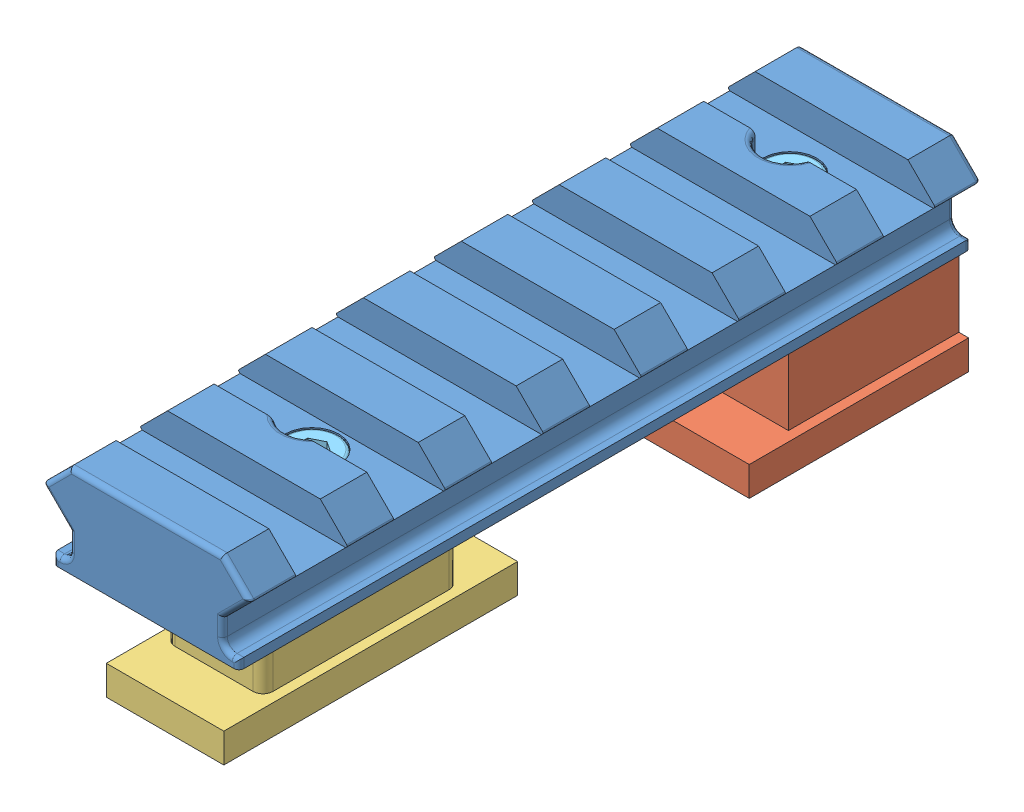
SolidWorks assembly Rail, configuration Standard. Lengths in mm.
Overall size (21.08 20.45 74.75).
7 component instances, 5 part files, 16 mates.
Components (placement in the parent):
- Rail-3: Rail [Standard] at (-4.1271 5.1584 0) size (21.08 9.45 74.75)
- flip_back-3: flip_back [Standard] at (-4.1271 -4.2416 0) x (0 0 1) z (-1 0 0) size (22.4 11 18.5)
- flip_front-1: flip_front [Standard] at (-4.1271 -4.2416 57.8) x (0 0 -1) z (1 0 0) size (30 11 12)
- hex nut style 1 gradeab_din-1: hex nut style 1 gradeab_din [Hexagon Nut ISO 4032 - M3 - D - S] at (-4.2271 -8.2416 9.0577) x (-1 0 0) z (0 1 0) size (5.5 6.35 2.4)
- hex nut style 1 gradeab_din-2: hex nut style 1 gradeab_din [Hexagon Nut ISO 4032 - M3 - D - S] at (-4.3271 -8.2416 57.8) x (1 0 0) z (0 1 0) size (5.5 6.35 2.4)
- socket head cap screw 4762_din-1: socket head cap screw 4762_din [ISO 4762 M3 x 10 --- 10S] at (-4.1271 2.1584 9) x (0 -1 0) z (-0.546944 0 0.837169) size (13 5.5 5.5)
- socket head cap screw 4762_din-2: socket head cap screw 4762_din [ISO 4762 M3 x 10 --- 10S] at (-4.1271 2.1584 57.8) x (0 -1 0) z (-0.546944 0 0.837169) size (13 5.5 5.5)
Mates (geometry in assembly coordinates):
- Deckungsgleich7: coincident: plane of Rail-3 through (5.3729 -4.2416 74.75) normal (0 -1 0); plane of flip_back-3 through (-13.3771 -4.2416 0) normal (0 1 0)
- Deckungsgleich11: coincident: plane of flip_front-1 through (1.8729 -4.2416 72.8) normal (0 1 0); plane of Rail-3 through (5.3729 -4.2416 74.75) normal (0 -1 0)
- Konzentrisch2: concentric: cylinder of Rail-3 through (-4.1271 2.1584 57.8) axis (0 1 0) radius 1.6; cylinder of flip_front-1 through (-4.1271 -27.3311 57.8) axis (0 1 0) radius 1.6
- Deckungsgleich12: coincident: plane of flip_back-3 through (-4.1271 -8.2416 12.2909) normal (0.5 0 -0.866025); plane of hex nut style 1 gradeab_din-1 through (-6.9771 -10.6416 10.6454) normal (-0.5 0 0.866025)
- Deckungsgleich13: coincident: plane of flip_front-1 through (-4.1271 -11.3311 61.0909) normal (0.5 0 -0.866025); plane of hex nut style 1 gradeab_din-2 through (-7.0771 -13.7311 59.3877) normal (-0.5 0 0.866025)
- Deckungsgleich14: coincident: plane of flip_front-1 through (-4.1271 -11.3311 57.8) normal (0 -1 0); plane of hex nut style 1 gradeab_din-2 through (-4.3271 -11.3311 54.6246) normal (0 1 0)
- Deckungsgleich16: coincident: plane of flip_back-3 through (-6.9771 -8.2416 10.6454) normal (1 0 0); plane of hex nut style 1 gradeab_din-1 through (-6.9771 -10.6416 10.6454) normal (-1 0 0)
- Deckungsgleich17: coincident: plane of flip_back-3 through (-4.1271 -8.2416 0) normal (0 -1 0); plane of hex nut style 1 gradeab_din-1 through (-4.2271 -8.2416 12.2332) normal (0 1 0)
- Deckungsgleich18: coincident: plane of flip_front-1 through (-6.9771 -11.3311 56.1546) normal (0.5 0 0.866025); plane of hex nut style 1 gradeab_din-2 through (-4.3271 -13.7311 54.6246) normal (-0.5 0 -0.866025)
- Konzentrisch7: concentric: cylinder of Rail-3 through (-4.1271 2.1584 57.8) axis (0 1 0) radius 1.6; cylinder of socket head cap screw 4762_din-2 through (-4.1271 33.9084 57.8) axis (0 1 0) radius 1.5
- Konzentrisch8: concentric: cylinder of Rail-3 through (-4.1271 2.1584 9) axis (0 1 0) radius 1.6; cylinder of socket head cap screw 4762_din-1 through (-4.1271 33.9084 9) axis (0 1 0) radius 1.5
- Deckungsgleich19: coincident: plane of Rail-3 through (-2.5271 -0.8416 9) normal (0 1 0); plane of socket head cap screw 4762_din-1 through (-1.8249 -0.8416 10.5041) normal (0 -1 0)
- Deckungsgleich20: coincident: plane of Rail-3 through (-2.5271 -0.8416 57.8) normal (0 1 0); plane of socket head cap screw 4762_din-2 through (-1.8249 -0.8416 59.3041) normal (0 -1 0)
- Konzentrisch9: concentric: cylinder of Rail-3 through (-4.1271 2.1584 9) axis (0 1 0) radius 1.6; cylinder of flip_back-3 through (-4.1271 -24.2416 9) axis (0 1 0) radius 1.6
- Parallel1: parallel: plane of Rail-3 through (-14.515 2.3584 0) normal (0 0 -1); plane of flip_back-3 through (5.1229 -15.2416 0) normal (0 0 -1)
- Parallel2: parallel: plane of Rail-3 through (-14.515 2.3584 74.75) normal (0 0 1); plane of flip_front-1 through (-9.1271 -15.3311 67.8) normal (0 0 1)
